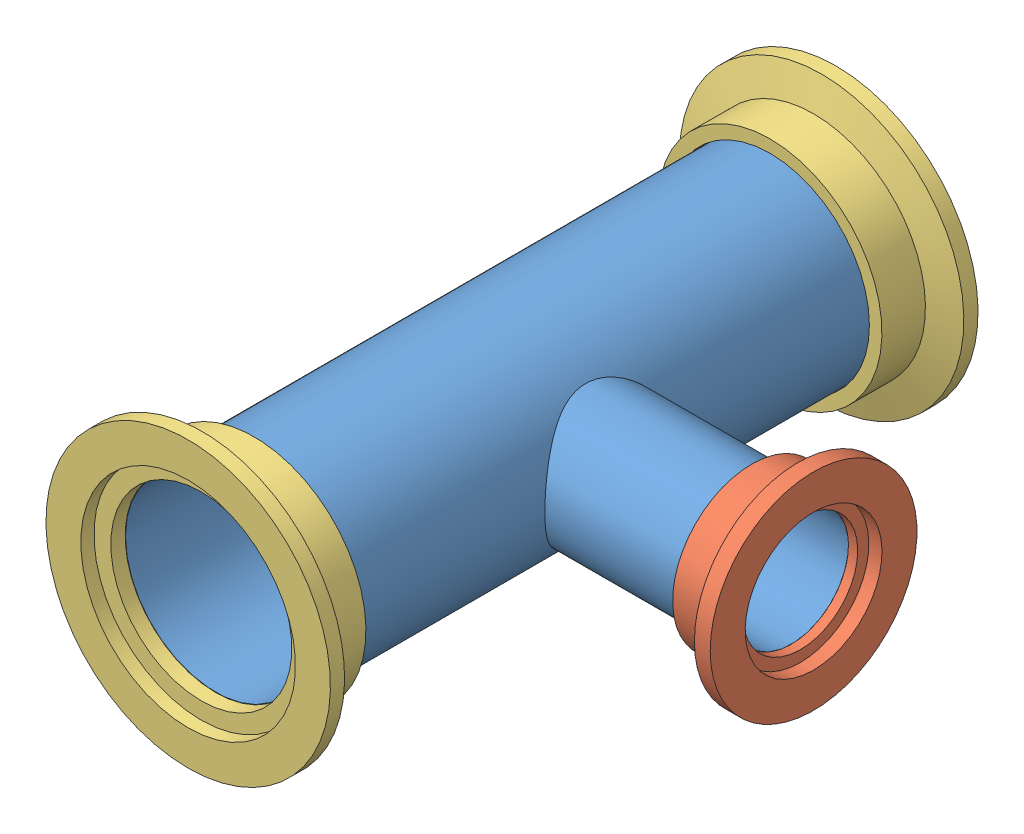
SolidWorks assembly 724012, configuration Default. Lengths in mm.
Overall size (85.6 54.86 124.92).
4 component instances, 3 part files, 6 mates.
Components (placement in the parent):
- 940441-1: 940441 [Default] at (28.3688 60.321 86.0761) size (72.9 38.1 114.3)
- 713002-1: 713002 [Default] at (86.5348 60.321 86.0761) x (0 -0.176751 0.984256) z (-1 0 0) size (39.88 39.88 11.94)
- 713003-99-1: 713003-99 [Default] at (28.3688 60.321 148.5347) x (1 0 0) z (0 -1 0) size (54.86 12.7 54.86)
- 713003-99-2: 713003-99 [Default] at (28.3688 60.321 23.6175) x (1 0 0) z (0 1 0) size (54.86 12.7 54.86)
Mates (geometry in assembly coordinates):
- Coincident1: coincident anti-aligned: plane of 940441-1 through (82.2168 60.321 86.0761) normal (1 0 0); plane of 713002-1 through (82.2168 58.0538 98.7012) normal (-1 0 0)
- Concentric1: concentric anti-aligned: cylinder of 940441-1 through (82.2168 60.321 86.0761) axis (-1 0 0) radius 12.7; cylinder of 713002-1 through (86.5348 60.321 86.0761) axis (1 0 0) radius 15.24
- Coincident2: coincident anti-aligned: plane of 940441-1 through (28.3688 60.321 143.2261) normal (0 0 1); plane of 713003-99-1 through (47.5458 60.321 143.2261) normal (0 0 -1)
- Concentric2: concentric anti-aligned: cylinder of 940441-1 through (28.3688 60.321 143.2261) axis (0 0 -1) radius 19.05; cylinder of 713003-99-1 through (28.3688 60.321 148.5347) axis (0 0 1) radius 21.59
- Coincident3: coincident anti-aligned: plane of 940441-1 through (28.3688 60.321 28.9261) normal (0 0 -1); plane of 713003-99-2 through (47.5458 60.321 28.9261) normal (0 0 1)
- Concentric3: concentric aligned: cylinder of 940441-1 through (28.3688 60.321 143.2261) axis (0 0 -1) radius 19.05; cylinder of 713003-99-2 through (28.3688 60.321 23.6175) axis (0 0 -1) radius 21.59
